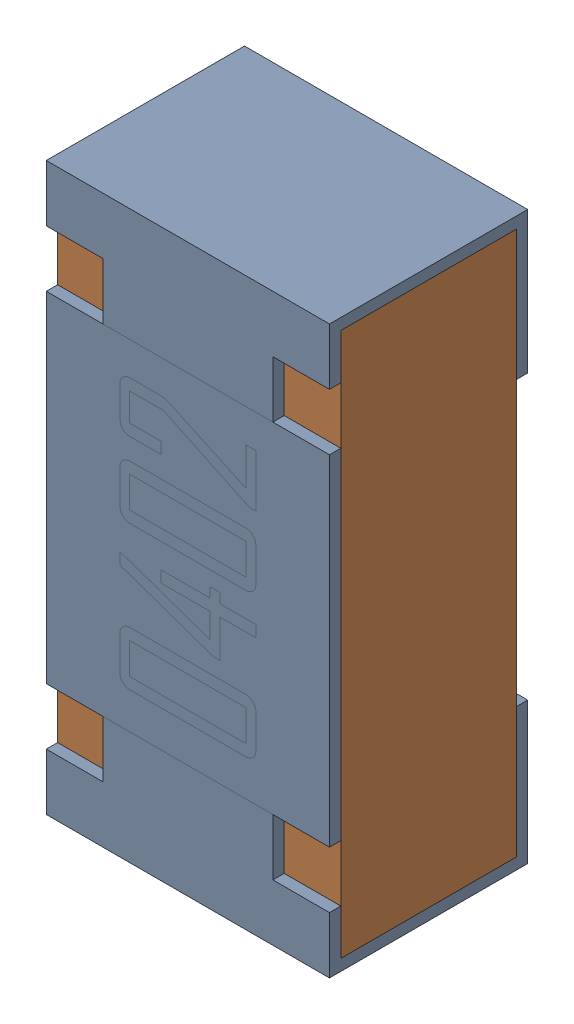
SolidWorks assembly R6, configuration Default. Lengths in mm.
Overall size (0.5 1 0.35).
3 component instances, 2 part files, 0 mates.
Components (placement in the parent):
- R6-subassembly-1-1: R6-subassembly-1 [Default] at (-9.5 7.7499 0) x (0 1 0) z (1 0 0) size (1 0.35 0.5)
  - 0402 resistor-1: 0402 resistor [Default] at origin size (1 0.35 0.5)
  - 0402 resistor-1-1: 0402 resistor-1 [Default] at origin size (0.96 0.31 0.5)
